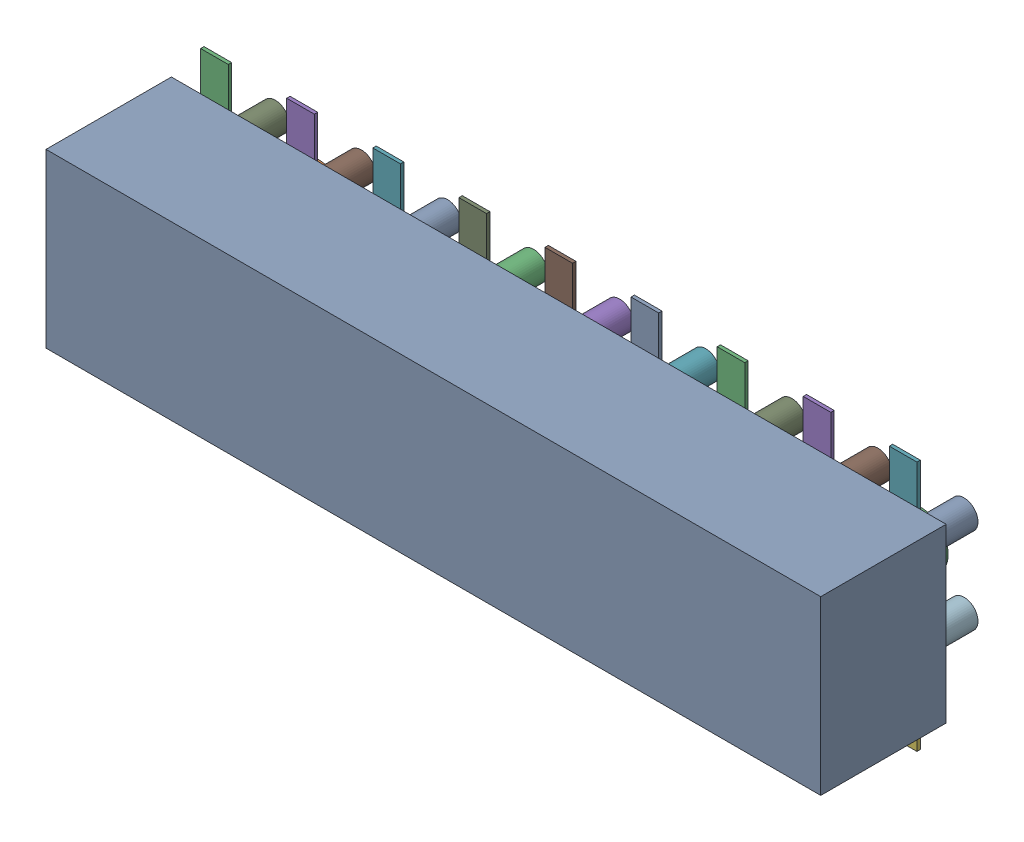
SolidWorks assembly Open CASCADE STEP translator 6.8 1.2.1, configuration Predeterminado. Lengths in mm.
Overall size (22.86 7.4 5.5).
42 component instances, 39 part files, 0 mates.
Components (placement in the parent):
- Body_1-1: Body_1 [Predeterminado] at origin size (22.86 7.4 5.5)
  - =_[0_1_1_2]-1: =_[0_1_1_2] [Predeterminado] at (0 0 0.1) size (22.86 5.08 3.7)
  - =_[0_1_1_3]-1: =_[0_1_1_3] [Predeterminado] at origin size (21.14 7.4 0.1)
    - SOLID-1: SOLID [Predeterminado] at origin size (0.82 1.58 0.1)
    - SOLID_2-1: SOLID_2 [Predeterminado] at origin size (0.82 1.58 0.1)
    - SOLID_3-1: SOLID_3 [Predeterminado] at origin size (0.82 1.58 0.1)
    - SOLID_4-1: SOLID_4 [Predeterminado] at origin size (0.82 1.58 0.1)
    - SOLID_5-1: SOLID_5 [Predeterminado] at origin size (0.82 1.58 0.1)
    - SOLID_6-1: SOLID_6 [Predeterminado] at origin size (0.82 1.58 0.1)
    - SOLID_7-1: SOLID_7 [Predeterminado] at origin size (0.82 1.58 0.1)
    - SOLID_8-1: SOLID_8 [Predeterminado] at origin size (0.82 1.58 0.1)
    - SOLID_9-1: SOLID_9 [Predeterminado] at origin size (0.82 1.58 0.1)
    - SOLID_10-1: SOLID_10 [Predeterminado] at origin size (0.82 1.58 0.1)
    - SOLID_11-1: SOLID_11 [Predeterminado] at origin size (0.82 1.58 0.1)
    - SOLID_12-1: SOLID_12 [Predeterminado] at origin size (0.82 1.58 0.1)
    - SOLID_13-1: SOLID_13 [Predeterminado] at origin size (0.82 1.58 0.1)
    - SOLID_14-1: SOLID_14 [Predeterminado] at origin size (0.82 1.58 0.1)
    - SOLID_15-1: SOLID_15 [Predeterminado] at origin size (0.82 1.58 0.1)
    - SOLID_16-1: SOLID_16 [Predeterminado] at origin size (0.82 1.58 0.1)
    - SOLID_17-1: SOLID_17 [Predeterminado] at origin size (0.82 1.58 0.1)
    - SOLID_18-1: SOLID_18 [Predeterminado] at origin size (0.82 1.58 0.1)
  - =_[0_1_1_4]-1: =_[0_1_1_4] [Predeterminado] at origin size (21.14 3.36 1.8)
    - SOLID_19-1: SOLID_19 [Predeterminado] at origin size (0.82 0.82 1.8)
    - SOLID_20-1: SOLID_20 [Predeterminado] at origin size (0.82 0.82 1.8)
    - SOLID_21-1: SOLID_21 [Predeterminado] at origin size (0.82 0.82 1.8)
    - SOLID_22-1: SOLID_22 [Predeterminado] at origin size (0.82 0.82 1.8)
    - SOLID_23-1: SOLID_23 [Predeterminado] at origin size (0.82 0.82 1.8)
    - SOLID_24-1: SOLID_24 [Predeterminado] at origin size (0.82 0.82 1.8)
    - SOLID_25-1: SOLID_25 [Predeterminado] at origin size (0.82 0.82 1.8)
    - SOLID_26-1: SOLID_26 [Predeterminado] at origin size (0.82 0.82 1.8)
    - SOLID_27-1: SOLID_27 [Predeterminado] at origin size (0.82 0.82 1.8)
    - SOLID_28-1: SOLID_28 [Predeterminado] at origin size (0.82 0.82 1.8)
    - SOLID_29-1: SOLID_29 [Predeterminado] at origin size (0.82 0.82 1.8)
    - SOLID_30-1: SOLID_30 [Predeterminado] at origin size (0.82 0.82 1.8)
    - SOLID_31-1: SOLID_31 [Predeterminado] at origin size (0.82 0.82 1.8)
    - SOLID_32-1: SOLID_32 [Predeterminado] at origin size (0.82 0.82 1.8)
    - SOLID_33-1: SOLID_33 [Predeterminado] at origin size (0.82 0.82 1.8)
    - SOLID_34-1: SOLID_34 [Predeterminado] at origin size (0.82 0.82 1.8)
    - SOLID_35-1: SOLID_35 [Predeterminado] at origin size (0.82 0.82 1.8)
    - SOLID_36-1: SOLID_36 [Predeterminado] at origin size (0.82 0.82 1.8)
    - SOLID_37-1: SOLID_37 [Predeterminado] at origin size (1.6 1.6 1.8)
    - SOLID_38-1: SOLID_38 [Predeterminado] at origin size (1.6 1.6 1.8)
